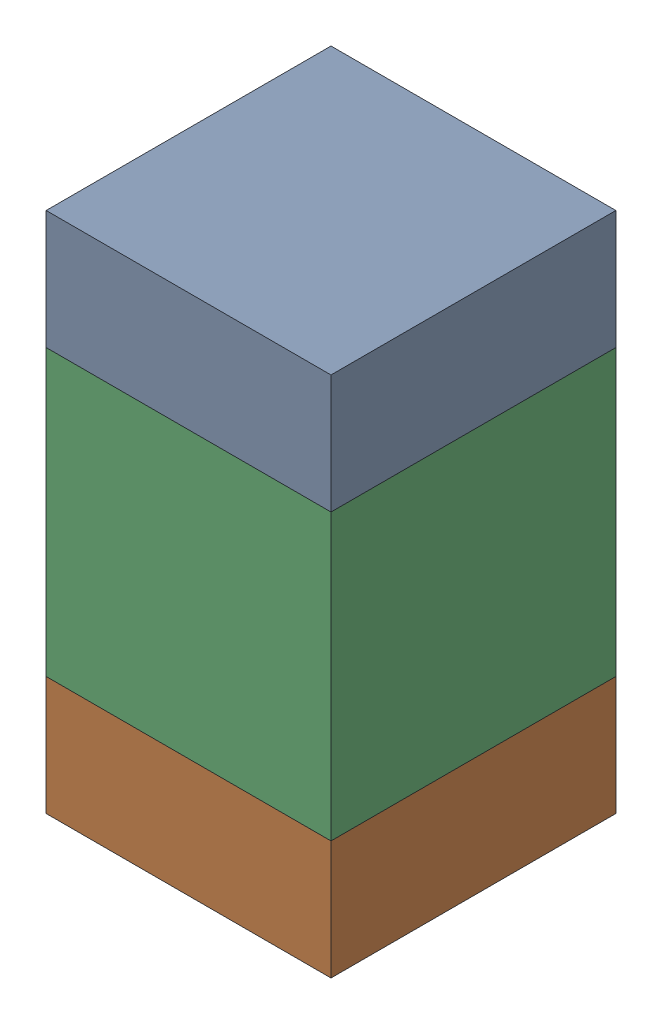
SolidWorks assembly C106_2PCB, configuration Default. Lengths in mm.
Overall size (0.6 1.1 0.6).
6 component instances, 2 part files, 0 mates.
Components (placement in the parent):
- 854785296-1: 854785296 [Default] at (102.9 85.025 0) size (0.6 0.25 0.6)
  - Extruded_10-1: Extruded_10 [Default] at origin size (0.6 0.25 0.6)
- 854785296-2: 854785296 [Default] at (102.9 84.175 0) size (0.6 0.25 0.6)
  - Extruded_10-1: Extruded_10 [Default] at origin size (0.6 0.25 0.6)
- 761606048-1: 761606048 [Default] at (102.9 84.6 0) size (0.6 0.6 0.6)
  - Extruded_9-1: Extruded_9 [Default] at origin size (0.6 0.6 0.6)
